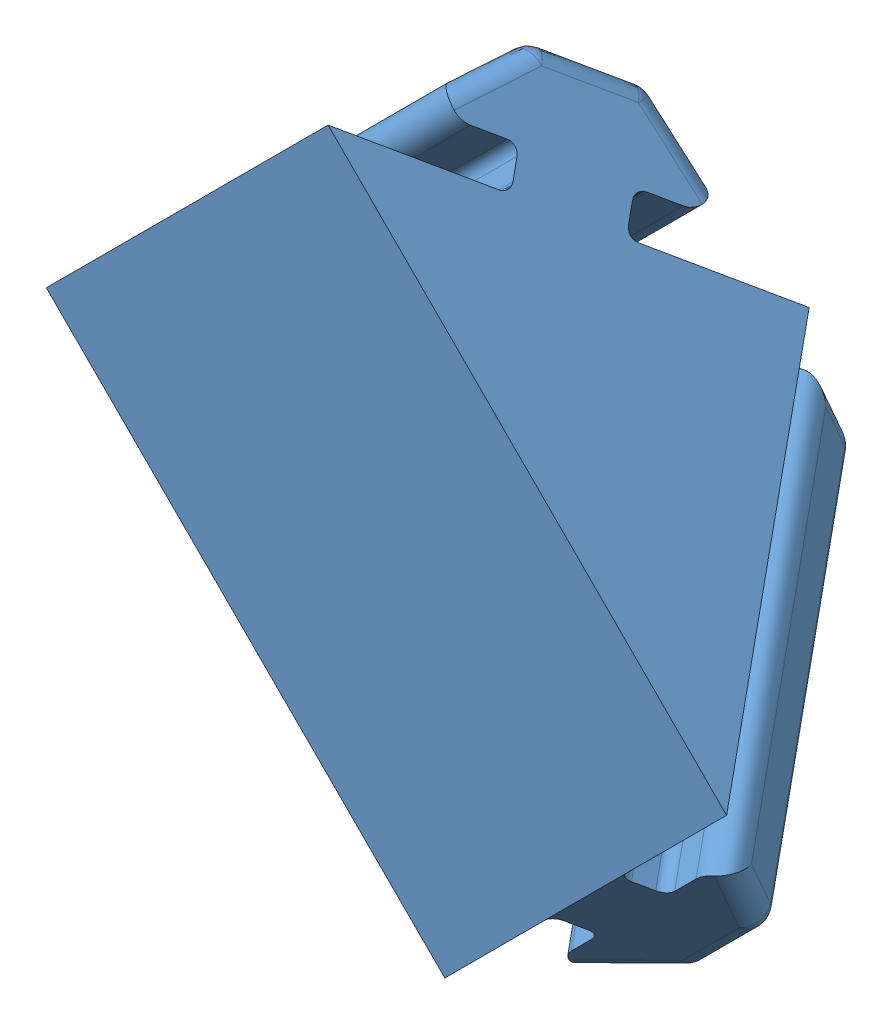
SolidWorks assembly 2020base_positioning_assem, configuration Default. Lengths in mm.
Overall size (40.34 40.34 37.05).
3 component instances, 2 part files, 4 mates.
Components (placement in the parent):
- Support_base_1-1: Support_base_1 [Default] at (0 0 118.3609) x (0.816497 0 -0.57735) z (0.408248 0.707107 0.57735) size (83.4 83.4 83.4) (hidden)
- reinforcer-1: reinforcer [Default] at (-67.8022 -26.6734 14.1421) x (0.5 -0.5 -0.707107) z (0.707107 0.707107 0) size (26.2 26.2 20)
- reinforcer-2: reinforcer [3 end] at (-77.2303 -36.1015 23.094) x (0.788675 -0.211325 -0.57735) z (0.57735 0.57735 0.57735) size (26.2 26.2 26.2) (hidden)
Mates (geometry in assembly coordinates):
- Coincident1: coincident: line of Support_base_1-1 through (0 0 83.7199) axis (0 0 1); plane of assembly
- Coincident2: coincident: line of Support_base_1-1 through (0 0 83.7199) axis (0 0 1); plane of assembly
- Coincident3: coincident aligned: plane of reinforcer-1 through (-67.8022 -26.6734 0) normal (0 0 1); plane of assembly through (0 0 0) normal (0 0 1)
- Coincident4: coincident aligned: plane of reinforcer-2 through (-77.2303 -36.1015 0) normal (0 0 1); plane of assembly through (0 0 0) normal (0 0 1)
